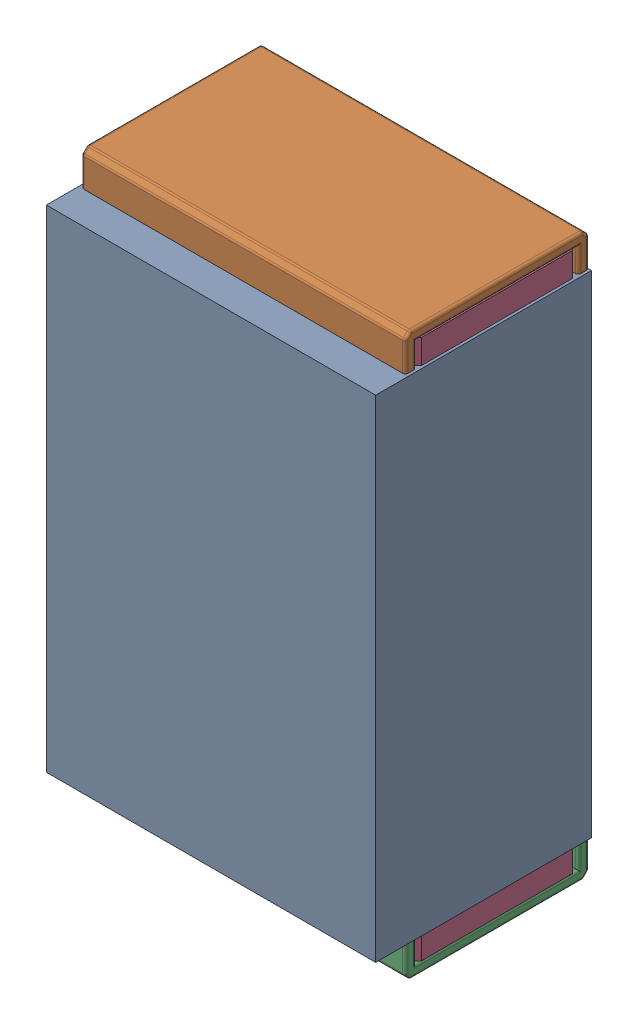
SolidWorks assembly R10, configuration Default. Lengths in mm.
Overall size (0.61 1.04 0.4).
3 component instances, 2 part files, 0 mates.
Components (placement in the parent):
- 1088881848-1: 1088881848 [Default] at (11.3 34.65 0) size (0.61 0.91 0.4)
  - Extruded-1-1: Extruded-1 [Default] at origin size (0.61 0.91 0.4)
- R0402-1: R0402 [Default] at (11.3 34.6501 0) x (0 1 0) z (1 0 0) size (1.04 0.34 0.6)
